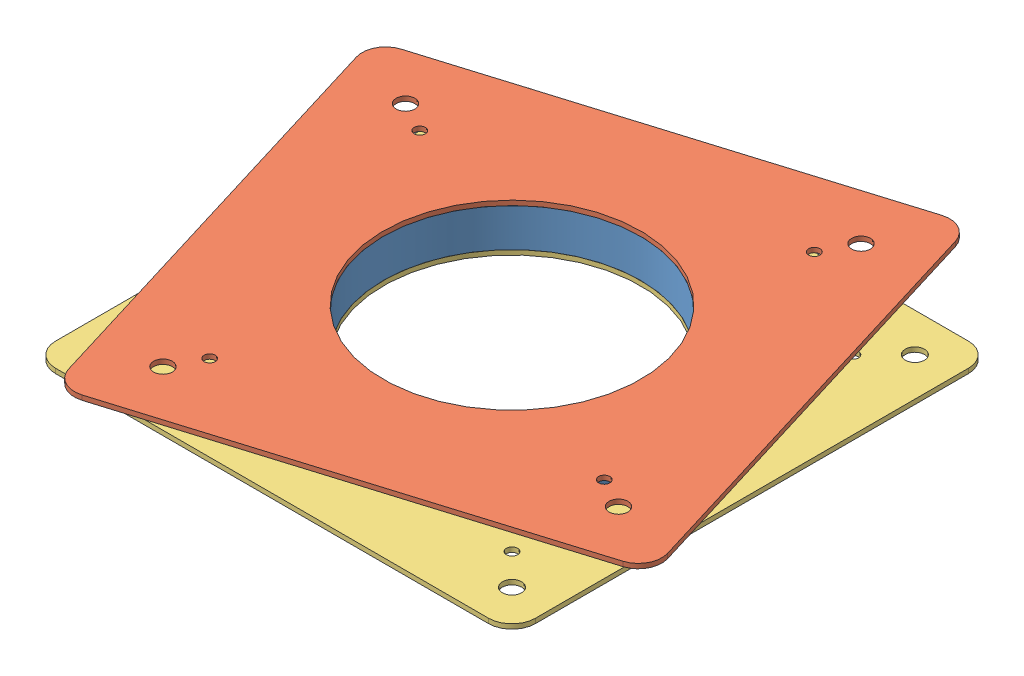
SolidWorks assembly lazy susan 102.4 diameter, configuration Default. Lengths in mm.
Overall size (127.82 77.77 127.82).
3 component instances, 3 part files, 2 mates.
Components (placement in the parent):
- lazy susan bearing mockup-1: lazy susan bearing mockup [Default] at (33.7917 35.6948 62.0888) size (81.07 8.15 81.07)
- lazy susan top 12.27 and 17.48-1: lazy susan top 12.27 and 17.48 [Default] at (33.7917 44.8448 62.0888) x (-0.956476 0 0.29181) z (-0.29181 0 -0.956476) size (102.4 68.62 102.4)
- lazy susan bottom 8.2 and 14.83-1: lazy susan bottom 8.2 and 14.83 [Default] at (33.7917 35.6948 62.0888) size (102.4 38.91 102.4)
Mates (geometry in assembly coordinates):
- Coincident1: coincident aligned: circle of lazy susan bearing mockup-1; circle of lazy susan bottom 8.2 and 14.83-1
- Coincident2: coincident anti-aligned: circle of lazy susan bearing mockup-1; circle of lazy susan top 12.27 and 17.48-1
